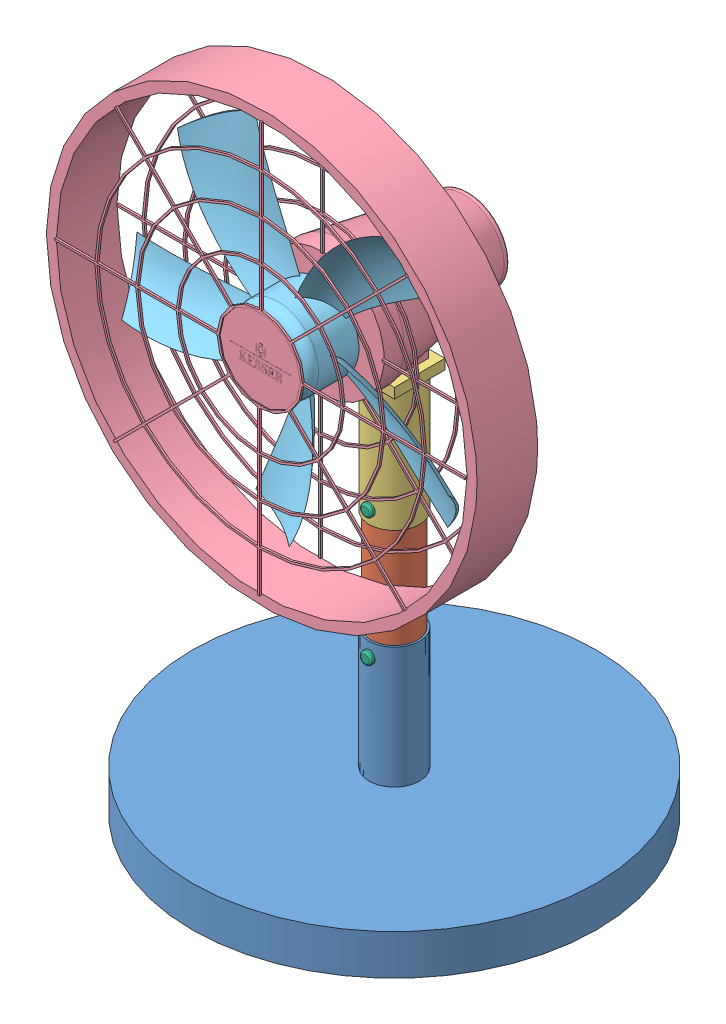
SolidWorks assembly Assem1, configuration По умолчанию. Lengths in mm.
Overall size (225.01 349.23 200).
8 component instances, 7 part files, 16 mates.
Components (placement in the parent):
- Part1-1: Part1 [Default] at (113.4303 78.689 114.2913) size (200 80 200)
- Part2-1: Part2 [Default] at (113.4303 98.689 114.2913) size (23 170 23)
- Part3-1: Part3 [По умолчанию] at (113.4303 208.689 114.2913) size (25.1 65 25.03)
- Part4-1: Part4 [По умолчанию] at (113.4303 306.689 79.915) size (213.11 213.11 103)
- Part5-1: Part5 [По умолчанию] at (113.4303 306.689 151.915) x (0.960142 0.279513 0) z (0 0 1) size (172.85 201.37 28)
- Part6-1: Part6 [По умолчанию] at (113.4303 215.309 121.701) x (0.883259 -0.468886 0) z (0 0 1) size (5.88 5.88 7)
- Part6-2: Part6 [По умолчанию] at (113.4303 152.0722 121.7913) x (0.14701 0.989135 0) z (0 0 1) size (5.88 5.88 7)
- Part7^Assem1-1: Part7^Assem1 [Default] at (113.4303 306.689 176.915) x (0.960142 0.279513 0) z (0 0 1) size (170.41 170.41 25) (hidden, virtual)
Mates (geometry in assembly coordinates):
- Coincident1: coincident: plane of Part1-1 through (113.4303 98.689 114.2913) normal (0 1 0); plane of Part2-1 through (113.4303 98.689 114.2913) normal (0 -1 0)
- Concentric1: concentric: circle of Part1-1; circle of Part2-1
- Tangent4: tangent: curve of Part1-1; circle of Part6-2
- Concentric4: concentric: cylinder of Part1-1 through (113.4303 152.0722 214.2923) axis (0 0 -1) radius 1.5; cylinder of Part6-2 through (113.4303 152.0722 126.7913) axis (0 0 -1) radius 1.5
- Coincident3: coincident: plane of Part2-1 through (113.4303 268.689 114.2913) normal (0 1 0); plane of Part3-1 through (113.4303 268.689 114.2913) normal (0 -1 0)
- Concentric5: concentric: circle of Part2-1; cylinder of Part3-1 through (113.4303 268.689 114.2913) axis (0 -1 0) radius 11.5
- Tangent5: tangent: curve of Part3-1; circle of Part6-1
- Concentric7: concentric: cylinder of Part3-1 through (113.4303 215.309 126.7923) axis (0 0 -1) radius 1.5; cylinder of Part6-1 through (113.4303 215.309 126.701) axis (0 0 -1) radius 1.5
- Coincident5: coincident: plane of Part3-1 through (113.4303 270.689 114.2913) normal (0 1 0); plane of Part4-1 through (113.4303 270.689 114.2913) normal (0 -1 0)
- Concentric8: concentric: circle of Part3-1; circle of Part4-1
- Concentric9: concentric: cylinder of Part4-1 through (113.4303 306.689 139.915) axis (0 0 1) radius 2.5; cylinder of Part5-1 through (113.4303 306.689 148.915) axis (0 0 1) radius 2.5
- Distance1: distance = 2 mm: plane of Part5-1 through (113.4303 306.689 151.915) normal (0 0 -1); plane of Part4-1 through (113.4303 306.689 149.915) normal (0 0 1)
- InPlace1: in place: plane of Part5-1 through (113.4303 306.689 176.915) normal (0 0 1); plane of ? through (0 0 176.915) normal (0 0 1); moOrthogonalPlaneRef_w of Part5-1 through (113.4303 306.689 176.915) normal (0 0 1); plane of ? through (0 0 176.915) normal (0 1 0); plane of Part5-1 through (113.4303 306.689 176.915) normal (0 0 1); plane of ? through (0 0 176.915) normal (1 0 0); plane of Part5-1 through (113.4303 306.689 176.915) normal (0 0 1); unknown of Part7^Assem1-1
- Coincident8: coincident: plane of Part5-1; plane of Part7^Assem1-1
- Coincident9: coincident: moOrthogonalPlaneRef_w of Part5-1 through (113.4303 306.689 176.915) normal (-0.279513 0.960142 0); plane of Part7^Assem1-1 through (113.4303 306.689 176.915) normal (-0.279513 0.960142 0)
- Coincident10: coincident: moOrthogonalPlaneRef_w of Part5-1 through (113.4303 306.689 176.915) normal (-0.960142 -0.279513 0); plane of Part7^Assem1-1 through (113.4303 306.689 176.915) normal (0.960142 0.279513 0)
